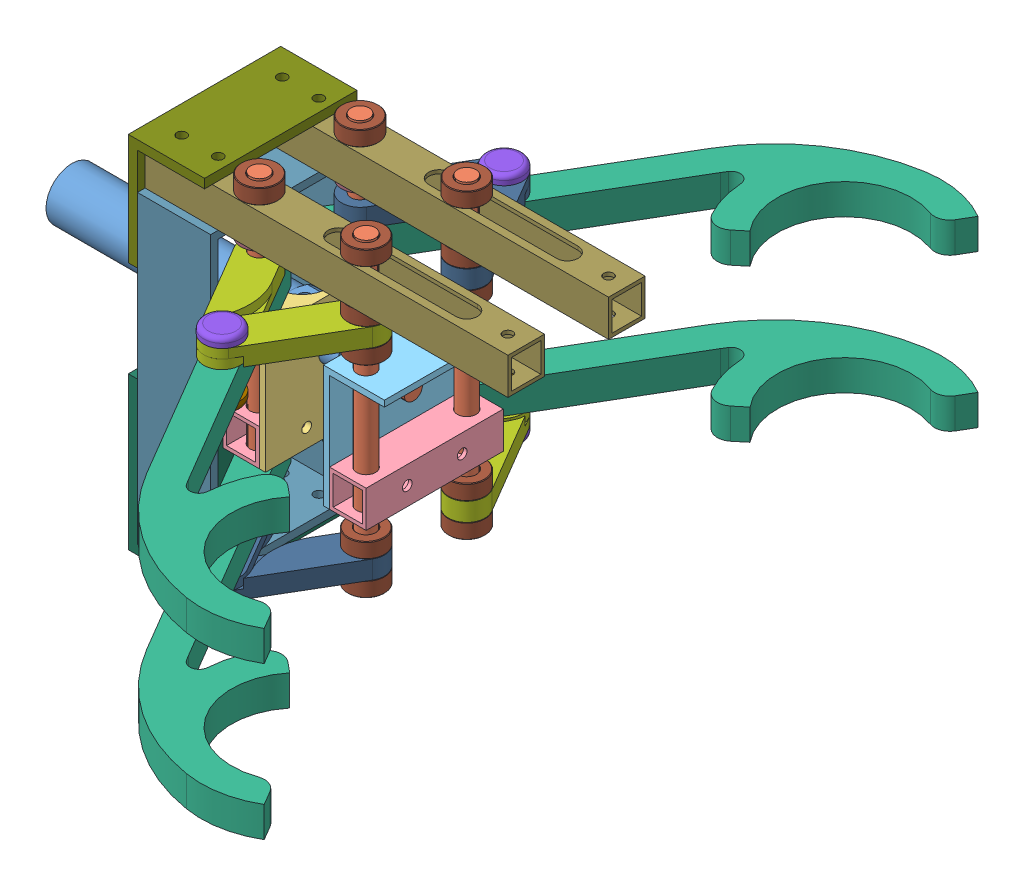
SolidWorks assembly hand_0302, configuration ﾃﾞﾌｫﾙﾄ. Lengths in mm.
Overall size (180.12 120.5 276.7).
52 component instances, 16 part files, 116 mates.
Components (placement in the parent):
- エアシリンダ_可動40-1: エアシリンダ_可動40 [ﾃﾞﾌｫﾙﾄ] at (65.512 -3.3304 50.561) x (1 0 0) z (0 1 0) size (112 17 17) (flexible)
  - ボディ_40-1: ボディ_40 [ﾃﾞﾌｫﾙﾄ] at (-67.4414 2.0168 92) size (92 17 17)
  - 軸_40-1: 軸_40 [ﾃﾞﾌｫﾙﾄ] at (-55.4414 2.0168 92) x (0 0.456107 -0.889925) z (1 0 0) size (6 6 100)
- l字-1: l字 [ﾃﾞﾌｫﾙﾄ] at (82.0707 63.6696 26.0442) x (0 0 1) z (-1 0 0) size (45 40 20)
- 偽l字-1: 偽l字 [ﾃﾞﾌｫﾙﾄ] at (82.0707 63.6696 71.0442) x (0 0 -1) z (1 0 0) size (45 12 12)
- l字改-1: l字改 [ﾃﾞﾌｫﾙﾄ] at (105.0707 63.6696 71.0442) x (0 0 -1) z (1 0 0) size (45 40 20)
- 偽l字-2: 偽l字 [ﾃﾞﾌｫﾙﾄ] at (117.0707 63.6696 71.0442) x (0 0 -1) z (1 0 0) size (45 12 12)
- 稲つかみ機構手 - コピー-1: 稲つかみ機構手 - コピー [ﾃﾞﾌｫﾙﾄ] at (114.8776 40.6696 140.8336) x (0.861801 0 -0.507246) z (0.507246 0 0.861801) size (42 10 148.45)
- 稲つかみ機構手 - コピー-2: 稲つかみ機構手 - コピー [ﾃﾞﾌｫﾙﾄ] at (114.8776 176.6696 -43.7451) x (0.861801 0 0.507246) z (0.507246 0 -0.861801) size (42 10 148.45)
- 稲つかみ機構手 - コピー-3: 稲つかみ機構手 - コピー [ﾃﾞﾌｫﾙﾄ] at (114.8776 -9.3304 140.8336) x (0.861801 0 -0.507246) z (0.507246 0 0.861801) size (42 10 148.45)
- 稲つかみ機構手 - コピー-4: 稲つかみ機構手 - コピー [ﾃﾞﾌｫﾙﾄ] at (114.8776 126.6696 -43.7451) x (0.861801 0 0.507246) z (0.507246 0 -0.861801) size (42 10 148.45)
- link-1: link [ﾃﾞﾌｫﾙﾄ] at (84.8207 113.6696 79.9103) x (0.507246 0 0.861801) z (-0.861801 0 0.507246) size (46.5 6 12)
- link-2: link [ﾃﾞﾌｫﾙﾄ] at (102.3207 119.6696 79.9103) x (-0.507246 0 0.861801) z (0.861801 0 0.507246) size (46.5 6 12)
- female-1: female [ﾃﾞﾌｫﾙﾄ] at (93.5707 122.6696 94.7764) x (-1 0 0) z (0 0 1) size (12 9 12)
- male-1: male [ﾃﾞﾌｫﾙﾄ] at (93.5707 100.6696 94.7764) size (12 18.8 12)
- link'-1: link' [ﾃﾞﾌｫﾙﾄ] at (84.8207 113.6696 17.1782) x (0.507246 0 -0.861801) z (0.861801 0 0.507246) size (46.5 6 12)
- link'-2: link' [ﾃﾞﾌｫﾙﾄ] at (102.3207 119.6696 17.1782) x (-0.507246 0 -0.861801) z (-0.861801 0 0.507246) size (46.5 6 12)
- female-2: female [ﾃﾞﾌｫﾙﾄ] at (93.5707 122.6696 2.3121) x (1 0 0) z (0 0 -1) size (12 9 12)
- male-2: male [ﾃﾞﾌｫﾙﾄ] at (93.5707 100.6696 2.3121) size (12 18.8 12)
- link-3: link [ﾃﾞﾌｫﾙﾄ] at (84.8207 53.6696 17.1782) x (0.507246 0 -0.861801) z (-0.861801 0 -0.507246) size (46.5 6 12)
- link-4: link [ﾃﾞﾌｫﾙﾄ] at (102.3207 47.6696 17.1782) x (-0.507246 0 -0.861801) z (0.861801 0 -0.507246) size (46.5 6 12)
- female-3: female [ﾃﾞﾌｫﾙﾄ] at (93.5707 44.6696 2.3121) size (12 9 12)
- male-3: male [ﾃﾞﾌｫﾙﾄ] at (93.5707 66.6696 2.3121) x (0.612505 0 -0.790466) z (-0.790466 0 -0.612505) size (12 18.8 12)
- link'-3: link' [ﾃﾞﾌｫﾙﾄ] at (84.8207 53.6696 79.9103) x (0.507246 0 0.861801) z (0.861801 0 -0.507246) size (46.5 6 12)
- link'-4: link' [ﾃﾞﾌｫﾙﾄ] at (102.3207 47.6696 79.9103) x (-0.507246 0 0.861801) z (-0.861801 0 -0.507246) size (46.5 6 12)
- female-4: female [ﾃﾞﾌｫﾙﾄ] at (93.5707 44.6696 94.7764) x (1 0 -0.000678) z (0.000678 0 1) size (12 9 12)
- male-4: male [ﾃﾞﾌｫﾙﾄ] at (93.5707 66.6696 94.7764) x (1 0 0) z (0 0 -1) size (12 18.8 12)
- セットカラー 内径6 外径12 厚さ5-1: セットカラー 内径6 外径12 厚さ5 [ﾃﾞﾌｫﾙﾄ] at (111.0707 58.6696 65.0442) x (0.999528 0 -0.030706) z (0 -1 0) size (12 12 5)
- セットカラー 内径6 外径12 厚さ5-2: セットカラー 内径6 外径12 厚さ5 [ﾃﾞﾌｫﾙﾄ] at (111.0707 53.6696 32.0442) x (-1 0 0) z (0 1 0) size (12 12 5)
- セットカラー 内径6 外径12 厚さ5-3: セットカラー 内径6 外径12 厚さ5 [ﾃﾞﾌｫﾙﾄ] at (111.0707 42.6696 65.0442) x (1 0 0) z (0 1 0) size (12 12 5)
- セットカラー 内径6 外径12 厚さ5-4: セットカラー 内径6 外径12 厚さ5 [ﾃﾞﾌｫﾙﾄ] at (111.0707 47.6696 32.0442) x (1 0 0) z (0 -1 0) size (12 12 5)
- セットカラー 内径6 外径12 厚さ5-5: セットカラー 内径6 外径12 厚さ5 [ﾃﾞﾌｫﾙﾄ] at (76.0707 47.6696 65.0442) x (1 0 0) z (0 -1 0) size (12 12 5)
- セットカラー 内径6 外径12 厚さ5-6: セットカラー 内径6 外径12 厚さ5 [ﾃﾞﾌｫﾙﾄ] at (76.0707 47.6696 32.0442) x (1 0 0) z (0 -1 0) size (12 12 5)
- セットカラー 内径6 外径12 厚さ5-7: セットカラー 内径6 外径12 厚さ5 [ﾃﾞﾌｫﾙﾄ] at (111.0707 113.6696 65.0442) x (1 0 0) z (0 -1 0) size (12 12 5)
- セットカラー 内径6 外径12 厚さ5-8: セットカラー 内径6 外径12 厚さ5 [ﾃﾞﾌｫﾙﾄ] at (111.0707 124.6696 65.0442) x (1 0 0) z (0 -1 0) size (12 12 5)
- セットカラー 内径6 外径12 厚さ5-9: セットカラー 内径6 外径12 厚さ5 [ﾃﾞﾌｫﾙﾄ] at (111.0707 113.6696 32.0442) x (1 0 0) z (0 -1 0) size (12 12 5)
- セットカラー 内径6 外径12 厚さ5-10: セットカラー 内径6 外径12 厚さ5 [ﾃﾞﾌｫﾙﾄ] at (111.0707 124.6696 32.0442) x (1 0 0) z (0 -1 0) size (12 12 5)
- 支え-1: 支え [ﾃﾞﾌｫﾙﾄ] at (13.5707 124.6696 71.0442) size (119 12 12)
- ブッシュ,内径６,外径８.1-1: ブッシュ,内径６,外径８.1 [ﾃﾞﾌｫﾙﾄ] at (80.1637 123.6696 63.0071) size (12 5.8 12)
- 支え-2: 支え [ﾃﾞﾌｫﾙﾄ] at (13.5707 124.6696 38.0442) size (119 12 12)
- ブッシュ,内径６,外径８.1-2: ブッシュ,内径６,外径８.1 [ﾃﾞﾌｫﾙﾄ] at (80.1637 123.6696 30.0071) size (12 5.8 12)
- 軸_40-1: 軸_40 [ﾃﾞﾌｫﾙﾄ] at (76.0707 142.1696 32.0442) x (1 0 0) z (0 -1 0) size (6 6 100)
- 軸_40-2: 軸_40 [ﾃﾞﾌｫﾙﾄ] at (76.0707 142.1696 65.0442) x (1 0 0) z (0 -1 0) size (6 6 100)
- 軸_40-3: 軸_40 [ﾃﾞﾌｫﾙﾄ] at (111.0707 142.1696 32.0442) x (-0.272872 0 0.96205) z (0 -1 0) size (6 6 100)
- 軸_40-4: 軸_40 [ﾃﾞﾌｫﾙﾄ] at (111.0707 142.1696 65.0442) x (1 0 0) z (0 -1 0) size (6 6 100)
- セットカラー 内径6 外径12 厚さ5-11: セットカラー 内径6 外径12 厚さ5 [ﾃﾞﾌｫﾙﾄ] at (76.0707 141.6696 32.0442) x (0.989147 0 -0.146932) z (0 -1 0) size (12 12 5)
- セットカラー 内径6 外径12 厚さ5-12: セットカラー 内径6 外径12 厚さ5 [ﾃﾞﾌｫﾙﾄ] at (76.0707 141.6696 65.0442) x (1 0 0) z (0 -1 0) size (12 12 5)
- セットカラー 内径6 外径12 厚さ5-13: セットカラー 内径6 外径12 厚さ5 [ﾃﾞﾌｫﾙﾄ] at (111.0707 141.6696 32.0442) x (1 0 0) z (0 -1 0) size (12 12 5)
- セットカラー 内径6 外径12 厚さ5-14: セットカラー 内径6 外径12 厚さ5 [ﾃﾞﾌｫﾙﾄ] at (111.0707 141.6696 65.0442) x (1 0 0) z (0 -1 0) size (12 12 5)
- 50×100角柱 24mm desu-1: 50×100角柱 24mm desu [ﾃﾞﾌｫﾙﾄ] at (44.5707 74.6696 48.5442) x (0 0 -1) z (1 0 0) size (50 100 24)
- 25x50L字x50＊2-1: 25x50L字x50＊2 [ﾃﾞﾌｫﾙﾄ] at (41.5707 71.6696 73.5442) x (0 0 -1) z (-1 0 0) size (50 50 25)
- 25x36.5(50L字)x50＊2-1: 25x36.5(50L字)x50＊2 [ﾃﾞﾌｫﾙﾄ] at (41.5707 89.6696 23.5442) x (0 0 1) z (-1 0 0) size (50 36.5 25)
Mates (geometry in assembly coordinates):
- 一致1: coincident anti-aligned: plane of エアシリンダ_可動40-1/ボディ_40-1 through (82.0707 88.6696 48.5442) normal (1 0 0); plane of l字-1 through (82.0707 101.6696 71.0442) normal (-1 0 0)
- 同心円1: concentric anti-aligned: circle of エアシリンダ_可動40-1/ボディ_40-1; circle of l字-1
- 平行1: parallel aligned: plane of エアシリンダ_可動40-1/ボディ_40-1 through (90.0707 97.1696 40.0442) normal (0 1 0); plane of l字-1 through (84.0707 103.6696 71.0442) normal (0 1 0)
- 一致4: coincident anti-aligned: plane of l字-1 through (82.0707 101.6696 71.0442) normal (-1 0 0); plane of 偽l字-1 through (82.0707 75.6696 26.0442) normal (1 0 0)
- 同心円2: concentric aligned: circle of l字-1; circle of 偽l字-1
- 同心円3: concentric aligned: circle of l字-1; circle of 偽l字-1
- 平行2: parallel aligned: plane of l字-1 through (84.0707 103.6696 71.0442) normal (0 1 0); plane of l字改-1 through (103.0707 103.6696 26.0442) normal (0 1 0)
- 同心円5: concentric aligned: circle of エアシリンダ_可動40-1/軸_40-1; circle of l字改-1
- 距離1: distance = 5 mm aligned: plane of l字改-1 through (105.0707 101.6696 26.0442) normal (1 0 0); plane of エアシリンダ_可動40-1/軸_40-1 through (110.0707 88.6696 48.5442) normal (1 0 0)
- 一致11: coincident anti-aligned: plane of l字改-1 through (105.0707 101.6696 26.0442) normal (1 0 0); plane of 偽l字-2 through (105.0707 75.6696 26.0442) normal (-1 0 0)
- 同心円6: concentric aligned: circle of l字改-1; circle of 偽l字-2
- 同心円7: concentric aligned: circle of l字改-1; circle of 偽l字-2
- 一致14: coincident anti-aligned: plane of l字-1 through (84.0707 103.6696 71.0442) normal (0 1 0); plane of 稲つかみ機構手 - コピー-1 through (156.6627 103.6696 169.5726) normal (0 -1 0)
- 同心円8: concentric anti-aligned: circle of l字-1; circle of 稲つかみ機構手 - コピー-1
- 一致16: coincident anti-aligned: plane of l字-1 through (84.0707 103.6696 71.0442) normal (0 1 0); plane of 稲つかみ機構手 - コピー-2 through (123.4956 103.6696 -38.6726) normal (0 -1 0)
- 同心円9: concentric aligned: circle of l字-1; circle of 稲つかみ機構手 - コピー-2
- 一致18: coincident anti-aligned: plane of 偽l字-1 through (82.0707 63.6696 26.0442) normal (0 -1 0); plane of 稲つかみ機構手 - コピー-3 through (123.4956 63.6696 135.7611) normal (0 1 0)
- 同心円10: concentric aligned: circle of 偽l字-1; circle of 稲つかみ機構手 - コピー-3
- 一致19: coincident anti-aligned: plane of 偽l字-1 through (82.0707 63.6696 26.0442) normal (0 -1 0); plane of 稲つかみ機構手 - コピー-4 through (156.6627 63.6696 -72.4841) normal (0 1 0)
- 同心円11: concentric anti-aligned: circle of 偽l字-1; circle of 稲つかみ機構手 - コピー-4
- 一致20: coincident anti-aligned: plane of 稲つかみ機構手 - コピー-1 through (123.4956 113.6696 135.7611) normal (0 1 0); plane of link-1 through (76.0707 113.6696 65.0442) normal (0 -1 0)
- 同心円12: concentric aligned: circle of 稲つかみ機構手 - コピー-1; circle of link-1
- 一致22: coincident aligned: plane of link-1 through (76.0707 113.6696 65.0442) normal (0 -1 0); plane of link-2 through (111.0707 113.6696 65.0442) normal (0 -1 0)
- 同心円13: concentric anti-aligned: circle of link-1; circle of link-2
- 同心円15: concentric aligned: circle of l字改-1; circle of link-2
- 一致26: coincident anti-aligned: plane of link-2 through (111.0707 119.6696 65.0442) normal (0 1 0); plane of female-1 through (93.5707 119.6696 94.7764) normal (0 -1 0)
- 同心円16: concentric aligned: circle of link-2; circle of female-1
- 一致27: coincident anti-aligned: cylinder of 稲つかみ機構手 - コピー-1; cylinder of male-1 through (93.5707 119.4696 94.7764) axis (0 -1 0) radius 3
- 一致28: coincident anti-aligned: plane of 稲つかみ機構手 - コピー-1 through (156.6627 103.6696 169.5726) normal (0 -1 0); plane of male-1 through (93.5707 103.6696 94.7764) normal (0 1 0)
- 同心円17: concentric anti-aligned: cylinder of female-1 through (93.5707 113.6696 94.7764) axis (0 1 0) radius 3.1; cylinder of male-1 through (93.5707 119.4696 94.7764) axis (0 -1 0) radius 3
- 一致29: coincident anti-aligned: plane of 稲つかみ機構手 - コピー-2 through (156.6627 113.6696 -72.4841) normal (0 1 0); plane of link'-1 through (76.0707 113.6696 32.0442) normal (0 -1 0)
- 一致30: coincident anti-aligned: circle of 稲つかみ機構手 - コピー-2; circle of link'-1
- 一致31: coincident aligned: plane of link'-1 through (76.0707 113.6696 32.0442) normal (0 -1 0); plane of link'-2 through (111.0707 113.6696 32.0442) normal (0 -1 0)
- 同心円18: concentric anti-aligned: circle of link'-1; circle of link'-2
- 同心円19: concentric aligned: circle of l字改-1; circle of link'-2
- 一致34: coincident anti-aligned: plane of link'-2 through (111.0707 119.6696 32.0442) normal (0 1 0); plane of female-2 through (93.5707 119.6696 2.3121) normal (0 -1 0)
- 同心円20: concentric aligned: circle of link'-2; circle of female-2
- 一致38: coincident anti-aligned: plane of 稲つかみ機構手 - コピー-2 through (123.4956 103.6696 -38.6726) normal (0 -1 0); plane of male-2 through (93.5707 103.6696 2.3121) normal (0 1 0)
- 同心円22: concentric anti-aligned: circle of 稲つかみ機構手 - コピー-2; circle of male-2
- 同心円23: concentric aligned: circle of 稲つかみ機構手 - コピー-4; circle of link-3
- 一致41: coincident anti-aligned: plane of 稲つかみ機構手 - コピー-4 through (123.4956 53.6696 -38.6726) normal (0 -1 0); plane of link-3 through (76.0707 53.6696 32.0442) normal (0 1 0)
- 一致42: coincident aligned: plane of link-3 through (76.0707 53.6696 32.0442) normal (0 1 0); plane of link-4 through (111.0707 53.6696 32.0442) normal (0 1 0)
- 同心円24: concentric aligned: circle of 偽l字-2; circle of link-4
- 同心円25: concentric aligned: cylinder of link-4 through (93.5707 53.6696 2.3121) axis (0 -1 0) radius 4.6; cylinder of female-3 through (93.5707 53.6696 2.3121) axis (0 -1 0) radius 4.5
- 一致43: coincident anti-aligned: plane of link-4 through (111.0707 47.6696 32.0442) normal (0 -1 0); plane of female-3 through (93.5707 47.6696 2.3121) normal (0 1 0)
- 同心円26: concentric anti-aligned: cylinder of link-3 through (93.5707 47.6696 2.3121) axis (0 1 0) radius 4.6; cylinder of female-3 through (93.5707 53.6696 2.3121) axis (0 -1 0) radius 4.5
- 同心円27: concentric anti-aligned: cylinder of female-2 through (93.5707 113.6696 2.3121) axis (0 1 0) radius 3.1; cylinder of male-2 through (93.5707 119.4696 2.3121) axis (0 -1 0) radius 3
- 同心円28: concentric anti-aligned: cylinder of female-3 through (93.5707 53.6696 2.3121) axis (0 -1 0) radius 3.1; cylinder of male-3 through (93.5707 47.8696 2.3121) axis (0 1 0) radius 3
- 同心円29: concentric anti-aligned: cylinder of 稲つかみ機構手 - コピー-4 through (93.5707 126.6696 2.3121) axis (0 -1 0) radius 3; cylinder of male-3 through (93.5707 47.8696 2.3121) axis (0 1 0) radius 3
- 一致44: coincident anti-aligned: plane of 稲つかみ機構手 - コピー-4 through (156.6627 63.6696 -72.4841) normal (0 1 0); plane of male-3 through (93.5707 63.6696 2.3121) normal (0 -1 0)
- 一致45: coincident anti-aligned: plane of 稲つかみ機構手 - コピー-3 through (156.6627 53.6696 169.5726) normal (0 -1 0); plane of link'-3 through (76.0707 53.6696 65.0442) normal (0 1 0)
- 同心円30: concentric anti-aligned: circle of 稲つかみ機構手 - コピー-3; circle of link'-3
- 同心円31: concentric anti-aligned: circle of 偽l字-2; cylinder of link'-4 through (111.0707 53.6696 65.0442) axis (0 -1 0) radius 3
- 一致48: coincident aligned: plane of link'-3 through (76.0707 53.6696 65.0442) normal (0 1 0); plane of link'-4 through (111.0707 53.6696 65.0442) normal (0 1 0)
- 同心円32: concentric aligned: cylinder of link'-4 through (93.5707 53.6696 94.7764) axis (0 -1 0) radius 4.6; cylinder of female-4 through (93.5707 53.6696 94.7764) axis (0 -1 0) radius 4.5
- 一致49: coincident anti-aligned: plane of link'-4 through (111.0707 47.6696 65.0442) normal (0 -1 0); plane of female-4 through (93.5707 47.6696 94.7764) normal (0 1 0)
- 同心円33: concentric anti-aligned: cylinder of link'-3 through (93.5707 47.6696 94.7764) axis (0 1 0) radius 4.6; cylinder of female-4 through (93.5707 53.6696 94.7764) axis (0 -1 0) radius 4.5
- 同心円34: concentric anti-aligned: cylinder of female-4 through (93.5707 53.6696 94.7764) axis (0 -1 0) radius 3.1; cylinder of male-4 through (93.5707 47.8696 94.7764) axis (0 1 0) radius 3
- 一致51: coincident anti-aligned: plane of 稲つかみ機構手 - コピー-3 through (123.4956 63.6696 135.7611) normal (0 1 0); plane of male-4 through (93.5707 63.6696 94.7764) normal (0 -1 0)
- 同心円35: concentric aligned: cylinder of 稲つかみ機構手 - コピー-3 through (93.5707 -9.3304 94.7764) axis (0 1 0) radius 3; cylinder of male-4 through (93.5707 47.8696 94.7764) axis (0 1 0) radius 3
- 一致52: coincident anti-aligned: plane of link'-4 through (111.0707 53.6696 65.0442) normal (0 1 0); plane of セットカラー 内径6 外径12 厚さ5-1 through (111.0707 53.6696 65.0442) normal (0 -1 0)
- 同心円36: concentric aligned: circle of link'-4; cylinder of セットカラー 内径6 外径12 厚さ5-1 through (111.0707 53.6696 65.0442) axis (0 1 0) radius 3
- 一致54: coincident anti-aligned: plane of link-4 through (111.0707 53.6696 32.0442) normal (0 1 0); plane of セットカラー 内径6 外径12 厚さ5-2 through (111.0707 53.6696 32.0442) normal (0 -1 0)
- 同心円37: concentric aligned: cylinder of セットカラー 内径6 外径12 厚さ5-2 through (111.0707 58.6696 32.0442) axis (0 -1 0) radius 3; cylinder of link-4 through (111.0707 53.6696 32.0442) axis (0 -1 0) radius 3
- 一致56: coincident anti-aligned: plane of link'-4 through (111.0707 47.6696 65.0442) normal (0 -1 0); plane of セットカラー 内径6 外径12 厚さ5-3 through (111.0707 47.6696 65.0442) normal (0 1 0)
- 同心円38: concentric aligned: cylinder of link'-4 through (111.0707 53.6696 65.0442) axis (0 -1 0) radius 3; cylinder of セットカラー 内径6 外径12 厚さ5-3 through (111.0707 47.6696 65.0442) axis (0 -1 0) radius 3
- 一致57: coincident anti-aligned: plane of link-4 through (111.0707 47.6696 32.0442) normal (0 -1 0); plane of セットカラー 内径6 外径12 厚さ5-4 through (111.0707 47.6696 32.0442) normal (0 1 0)
- 同心円39: concentric anti-aligned: cylinder of link-4 through (111.0707 53.6696 32.0442) axis (0 -1 0) radius 3; cylinder of セットカラー 内径6 外径12 厚さ5-4 through (111.0707 42.6696 32.0442) axis (0 1 0) radius 3
- 一致58: coincident anti-aligned: plane of link'-3 through (76.0707 47.6696 65.0442) normal (0 -1 0); plane of セットカラー 内径6 外径12 厚さ5-5 through (76.0707 47.6696 65.0442) normal (0 1 0)
- 同心円40: concentric aligned: cylinder of link'-3 through (76.0707 47.6696 65.0442) axis (0 1 0) radius 3; cylinder of セットカラー 内径6 外径12 厚さ5-5 through (76.0707 42.6696 65.0442) axis (0 1 0) radius 3
- 一致59: coincident anti-aligned: plane of link-3 through (76.0707 47.6696 32.0442) normal (0 -1 0); plane of セットカラー 内径6 外径12 厚さ5-6 through (76.0707 47.6696 32.0442) normal (0 1 0)
- 同心円41: concentric aligned: cylinder of link-3 through (76.0707 47.6696 32.0442) axis (0 1 0) radius 3; cylinder of セットカラー 内径6 外径12 厚さ5-6 through (76.0707 42.6696 32.0442) axis (0 1 0) radius 3
- 一致60: coincident anti-aligned: plane of link-2 through (111.0707 113.6696 65.0442) normal (0 -1 0); plane of セットカラー 内径6 外径12 厚さ5-7 through (111.0707 113.6696 65.0442) normal (0 1 0)
- 同心円42: concentric aligned: cylinder of link-2 through (111.0707 113.6696 65.0442) axis (0 1 0) radius 3; cylinder of セットカラー 内径6 外径12 厚さ5-7 through (111.0707 108.6696 65.0442) axis (0 1 0) radius 3
- 一致61: coincident anti-aligned: plane of link-2 through (111.0707 119.6696 65.0442) normal (0 1 0); plane of セットカラー 内径6 外径12 厚さ5-8 through (111.0707 119.6696 65.0442) normal (0 -1 0)
- 同心円43: concentric aligned: cylinder of セットカラー 内径6 外径12 厚さ5-8 through (111.0707 119.6696 65.0442) axis (0 1 0) radius 3; cylinder of link-2 through (111.0707 113.6696 65.0442) axis (0 1 0) radius 3
- 一致62: coincident anti-aligned: plane of link'-2 through (111.0707 113.6696 32.0442) normal (0 -1 0); plane of セットカラー 内径6 外径12 厚さ5-9 through (111.0707 113.6696 32.0442) normal (0 1 0)
- 同心円44: concentric aligned: cylinder of link'-2 through (111.0707 113.6696 32.0442) axis (0 1 0) radius 3; cylinder of セットカラー 内径6 外径12 厚さ5-9 through (111.0707 108.6696 32.0442) axis (0 1 0) radius 3
- 一致63: coincident anti-aligned: plane of link'-2 through (111.0707 119.6696 32.0442) normal (0 1 0); plane of セットカラー 内径6 外径12 厚さ5-10 through (111.0707 119.6696 32.0442) normal (0 -1 0)
- 同心円45: concentric aligned: cylinder of link'-2 through (111.0707 113.6696 32.0442) axis (0 1 0) radius 3; cylinder of セットカラー 内径6 外径12 厚さ5-10 through (111.0707 119.6696 32.0442) axis (0 1 0) radius 3
- 一致64: coincident anti-aligned: plane of セットカラー 内径6 外径12 厚さ5-8 through (111.0707 124.6696 65.0442) normal (0 1 0); plane of 支え-1 through (163.5707 124.6696 71.0442) normal (0 -1 0)
- 一致65: coincident anti-aligned: plane of 支え-1 through (163.5707 124.6696 71.0442) normal (0 -1 0); plane of ブッシュ,内径６,外径８.1-1 through (76.0707 124.6696 65.0442) normal (0 1 0)
- 同心円46: concentric anti-aligned: cylinder of 支え-1 through (76.0707 124.6696 65.0442) axis (0 1 0) radius 4.05; cylinder of ブッシュ,内径６,外径８.1-1 through (76.0707 129.4696 65.0442) axis (0 -1 0) radius 4.05
- 同心円47: concentric aligned: cylinder of link-1 through (76.0707 119.6696 65.0442) axis (0 -1 0) radius 3; cylinder of ブッシュ,内径６,外径８.1-1 through (76.0707 129.4696 65.0442) axis (0 -1 0) radius 3.05
- 平行3: parallel aligned: plane of エアシリンダ_可動40-1/ボディ_40-1 through (90.0707 80.1696 57.0442) normal (0 0 1); plane of 支え-1 through (163.5707 136.6696 71.0442) normal (0 0 1)
- 一致67: coincident anti-aligned: plane of セットカラー 内径6 外径12 厚さ5-10 through (111.0707 124.6696 32.0442) normal (0 1 0); plane of 支え-2 through (163.5707 124.6696 38.0442) normal (0 -1 0)
- 平行4: parallel aligned: plane of エアシリンダ_可動40-1/ボディ_40-1 through (90.0707 80.1696 40.0442) normal (0 0 -1); plane of 支え-2 through (163.5707 136.6696 26.0442) normal (0 0 -1)
- 一致69: coincident anti-aligned: plane of 支え-2 through (163.5707 124.6696 38.0442) normal (0 -1 0); plane of ブッシュ,内径６,外径８.1-2 through (76.0707 124.6696 32.0442) normal (0 1 0)
- 同心円48: concentric anti-aligned: cylinder of 支え-2 through (76.0707 124.6696 32.0442) axis (0 1 0) radius 4.05; cylinder of ブッシュ,内径６,外径８.1-2 through (76.0707 129.4696 32.0442) axis (0 -1 0) radius 4.05
- 同心円49: concentric aligned: cylinder of link'-1 through (76.0707 119.6696 32.0442) axis (0 -1 0) radius 3; cylinder of ブッシュ,内径６,外径８.1-2 through (76.0707 129.4696 32.0442) axis (0 -1 0) radius 3.05
- 同心円50: concentric aligned: cylinder of セットカラー 内径6 外径12 厚さ5-6 through (76.0707 42.6696 32.0442) axis (0 1 0) radius 3; cylinder of 軸_40-1 through (76.0707 42.1696 32.0442) axis (0 1 0) radius 3
- 同心円51: concentric aligned: cylinder of セットカラー 内径6 外径12 厚さ5-5 through (76.0707 42.6696 65.0442) axis (0 1 0) radius 3; cylinder of 軸_40-2 through (76.0707 42.1696 65.0442) axis (0 1 0) radius 3
- 同心円52: concentric aligned: cylinder of セットカラー 内径6 外径12 厚さ5-4 through (111.0707 42.6696 32.0442) axis (0 1 0) radius 3; cylinder of 軸_40-3 through (111.0707 42.1696 32.0442) axis (0 1 0) radius 3
- 同心円53: concentric anti-aligned: cylinder of セットカラー 内径6 外径12 厚さ5-3 through (111.0707 47.6696 65.0442) axis (0 -1 0) radius 3; cylinder of 軸_40-4 through (111.0707 42.1696 65.0442) axis (0 1 0) radius 3
- 同心円54: concentric aligned: cylinder of 軸_40-1 through (76.0707 42.1696 32.0442) axis (0 1 0) radius 3; cylinder of セットカラー 内径6 外径12 厚さ5-11 through (76.0707 136.6696 32.0442) axis (0 1 0) radius 3
- 一致74: coincident anti-aligned: plane of 支え-2 through (163.5707 136.6696 38.0442) normal (0 1 0); plane of セットカラー 内径6 外径12 厚さ5-11 through (76.0707 136.6696 32.0442) normal (0 -1 0)
- 距離2: distance = 0.5 mm aligned: plane of セットカラー 内径6 外径12 厚さ5-6 through (76.0707 42.6696 32.0442) normal (0 -1 0); plane of 軸_40-1 through (76.0707 42.1696 32.0442) normal (0 -1 0)
- 距離3: distance = 0.5 mm aligned: plane of セットカラー 内径6 外径12 厚さ5-5 through (76.0707 42.6696 65.0442) normal (0 -1 0); plane of 軸_40-2 through (76.0707 42.1696 65.0442) normal (0 -1 0)
- 距離4: distance = 0.5 mm aligned: plane of セットカラー 内径6 外径12 厚さ5-4 through (111.0707 42.6696 32.0442) normal (0 -1 0); plane of 軸_40-3 through (111.0707 42.1696 32.0442) normal (0 -1 0)
- 距離5: distance = 0.5 mm aligned: plane of セットカラー 内径6 外径12 厚さ5-3 through (111.0707 42.6696 65.0442) normal (0 -1 0); plane of 軸_40-4 through (111.0707 42.1696 65.0442) normal (0 -1 0)
- 一致75: coincident anti-aligned: plane of 支え-1 through (163.5707 136.6696 71.0442) normal (0 1 0); plane of セットカラー 内径6 外径12 厚さ5-12 through (76.0707 136.6696 65.0442) normal (0 -1 0)
- 同心円55: concentric aligned: cylinder of 軸_40-2 through (76.0707 42.1696 65.0442) axis (0 1 0) radius 3; cylinder of セットカラー 内径6 外径12 厚さ5-12 through (76.0707 136.6696 65.0442) axis (0 1 0) radius 3
- 一致76: coincident anti-aligned: plane of 支え-2 through (163.5707 136.6696 38.0442) normal (0 1 0); plane of セットカラー 内径6 外径12 厚さ5-13 through (111.0707 136.6696 32.0442) normal (0 -1 0)
- 同心円56: concentric aligned: cylinder of 軸_40-3 through (111.0707 42.1696 32.0442) axis (0 1 0) radius 3; cylinder of セットカラー 内径6 外径12 厚さ5-13 through (111.0707 136.6696 32.0442) axis (0 1 0) radius 3
- 一致77: coincident anti-aligned: plane of 支え-1 through (163.5707 136.6696 71.0442) normal (0 1 0); plane of セットカラー 内径6 外径12 厚さ5-14 through (111.0707 136.6696 65.0442) normal (0 -1 0)
- 同心円57: concentric aligned: cylinder of 軸_40-4 through (111.0707 42.1696 65.0442) axis (0 1 0) radius 3; cylinder of セットカラー 内径6 外径12 厚さ5-14 through (111.0707 136.6696 65.0442) axis (0 1 0) radius 3
- 一致78: coincident aligned: plane of 支え-2 through (44.5707 124.6696 38.0442) normal (-1 0 0); plane of 50×100角柱 24mm desu-1 through (44.5707 74.6696 48.5442) normal (-1 0 0)
- 同心円58: concentric anti-aligned: circle of 支え-2; circle of 50×100角柱 24mm -1
- 同心円59: concentric anti-aligned: circle of 支え-1; circle of 50×100角柱 24mm -1
- 一致82: coincident anti-aligned: plane of 支え-2 through (163.5707 124.6696 38.0442) normal (0 -1 0); plane of 50×100角柱 24mm desu-1 through (68.5707 124.6696 73.5442) normal (0 1 0)
- 一致83: coincident anti-aligned: plane of 50×100角柱 24mm desu-1 through (68.5707 24.6696 73.5442) normal (0 -1 0); plane of 25x50L字x50-1 through (66.5707 24.6696 23.5442) normal (0 1 0)
- 同心円60: concentric aligned: circle of 50×100角柱 24mm -1; circle of 25x50L字-1
- 同心円61: concentric aligned: circle of 50×100角柱 24mm -1; circle of 25x50L字-1
- 一致86: coincident anti-aligned: plane of 支え-1 through (163.5707 136.6696 71.0442) normal (0 1 0); plane of 25x36.5(50L字)x50-1 through (66.5707 136.6696 73.5442) normal (0 -1 0)
- 同心円62: concentric anti-aligned: circle of 支え-1; cylinder of 25x36.5(50L字)x50-1 through (62.5707 139.6696 65.0442) axis (0 -1 0) radius 1.6
- 同心円63: concentric anti-aligned: cylinder of 支え-2 through (50.5707 124.6696 32.0442) axis (0 1 0) radius 1.6; circle of 25x50L字_36.5-1
